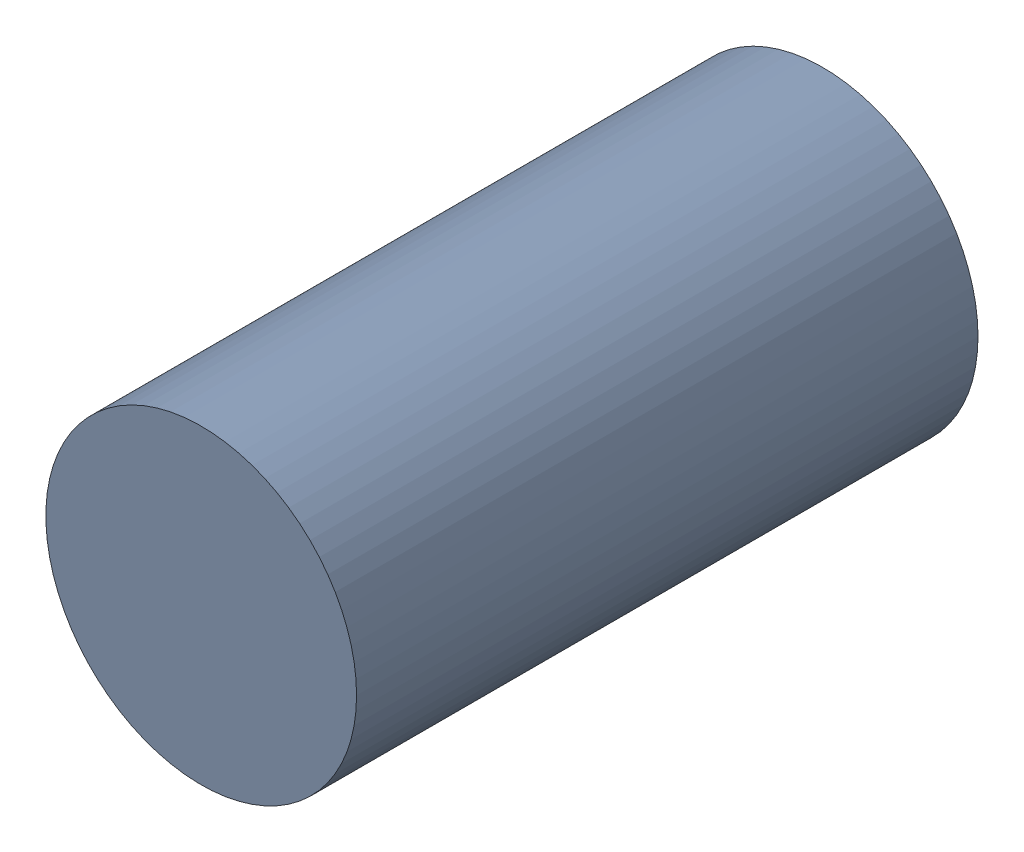
SolidWorks assembly MH9, configuration Default. Lengths in mm.
Overall size (1 1 2).
2 component instances, 1 part files, 0 mates.
Components (placement in the parent):
- 9228463120-1: 9228463120 [Default] at (48.979 80.6107 -1.5) size (1 1 2)
  - Cylinder-1: Cylinder [Default] at origin size (1 1 2)
